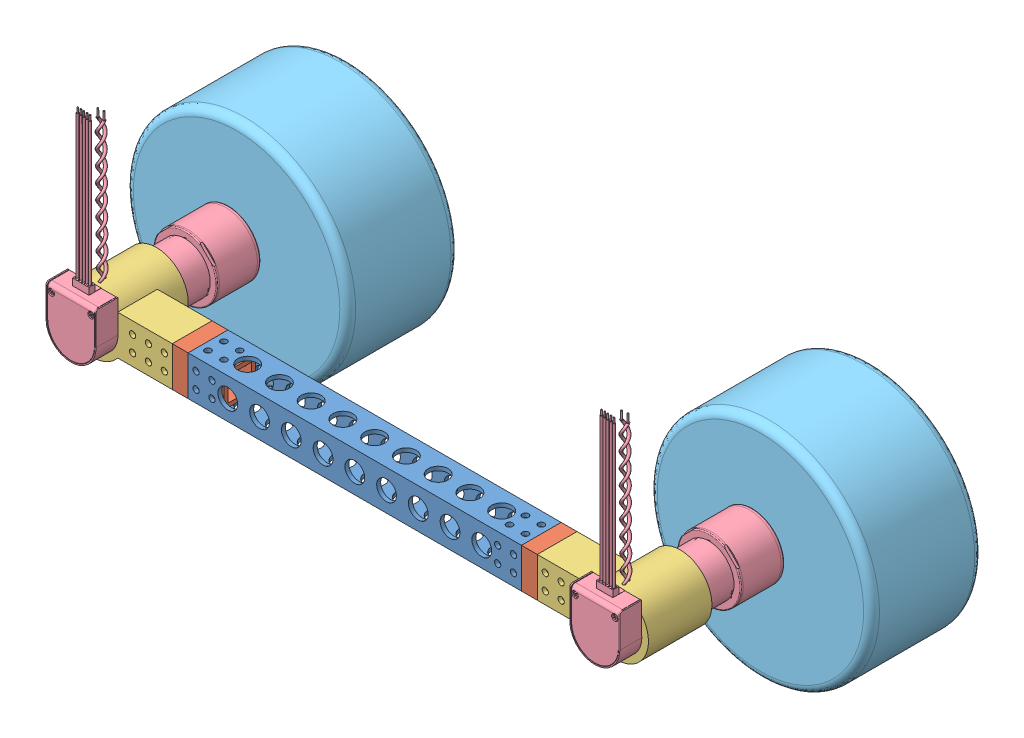
SolidWorks assembly One side drivetrain subassembly, configuration Default. Lengths in mm.
Overall size (596.9 246.35 221.71).
9 component instances, 5 part files, 20 mates.
Components (placement in the parent):
- 10.5in box extrusion-1: 10.5in box extrusion [Default] at (70.3566 -7.0157 32.9173) size (266.7 31.75 31.75)
- Extrusion to motor mount adapter-1: Extrusion to motor mount adapter [Default] at (108.4566 -10.1907 61.4923) x (0 0 1) z (-1 0 0) size (31.75 31.75 63.5)
- Extrusion to motor mount adapter-2: Extrusion to motor mount adapter [Default] at (-234.4434 -10.1907 36.0923) x (0 0 -1) z (1 0 0) size (31.75 31.75 63.5)
- Motor mount-1: Motor mount [Default] at (146.5566 -22.8907 13.8673) size (88.9 50.8 50.8)
- Motor mount-2: Motor mount [Default] at (-272.5434 -22.8907 13.8673) x (-1 0 0) z (0 0 1) size (88.9 50.8 50.8)
- GM9236S025-R1-SP_dc_motor_CAD-1: GM9236S025-R1-SP_dc_motor_CAD [Default] at (-272.5434 -22.8907 64.6673) size (52.61 175.4 145.51)
- GM9236S025-R1-SP_dc_motor_CAD-2: GM9236S025-R1-SP_dc_motor_CAD [Default] at (146.5566 -22.8907 64.6673) size (52.61 175.4 145.51)
- wheel-1: wheel [Default] at (146.5566 -31.2473 -139.2185) size (177.8 177.8 88.9)
- wheel-2: wheel [Default] at (-272.5434 -31.2473 -139.2185) size (177.8 177.8 88.9)
Mates (geometry in assembly coordinates):
- Coincident2: coincident anti-aligned: plane of 10.5in box extrusion-1 through (-196.3434 -10.1907 61.4923) normal (0 -1 0); plane of Extrusion to motor mount adapter-1 through (44.9566 -10.1907 36.0923) normal (0 1 0)
- Coincident3: coincident anti-aligned: plane of 10.5in box extrusion-1 through (-196.3434 -10.1907 61.4923) normal (0 0 -1); plane of Extrusion to motor mount adapter-1 through (44.9566 -10.1907 61.4923) normal (0 0 1)
- Coincident4: coincident anti-aligned: plane of 10.5in box extrusion-1 through (70.3566 -7.0157 64.6673) normal (1 0 0); plane of Extrusion to motor mount adapter-1 through (70.3566 -10.1907 61.4923) normal (-1 0 0)
- Coincident5: coincident anti-aligned: plane of 10.5in box extrusion-1 through (-196.3434 -10.1907 61.4923) normal (0 -1 0); plane of Extrusion to motor mount adapter-2 through (-170.9434 -10.1907 61.4923) normal (0 1 0)
- Coincident6: coincident anti-aligned: plane of 10.5in box extrusion-1 through (-196.3434 -10.1907 61.4923) normal (0 0 -1); plane of Extrusion to motor mount adapter-2 through (-170.9434 -10.1907 61.4923) normal (0 0 1)
- Coincident7: coincident anti-aligned: plane of 10.5in box extrusion-1 through (-196.3434 -7.0157 64.6673) normal (-1 0 0); plane of Extrusion to motor mount adapter-2 through (-196.3434 -10.1907 36.0923) normal (1 0 0)
- Coincident8: coincident anti-aligned: plane of Extrusion to motor mount adapter-1 through (83.0566 -10.1907 61.4923) normal (0 1 0); plane of Motor mount-1 through (121.1566 -10.1907 36.0923) normal (0 -1 0)
- Coincident9: coincident anti-aligned: plane of Extrusion to motor mount adapter-1 through (83.0566 -10.1907 61.4923) normal (0 0 1); plane of Motor mount-1 through (121.1566 -10.1907 61.4923) normal (0 0 -1)
- Coincident10: coincident anti-aligned: plane of Extrusion to motor mount adapter-1 through (83.0566 -10.1907 61.4923) normal (1 0 0); plane of Motor mount-1 through (83.0566 -7.0157 32.9173) normal (-1 0 0)
- Coincident11: coincident anti-aligned: plane of Extrusion to motor mount adapter-2 through (-209.0434 -35.5907 36.0923) normal (0 -1 0); plane of Motor mount-2 through (-247.1434 -35.5907 36.0923) normal (0 1 0)
- Coincident12: coincident anti-aligned: plane of Extrusion to motor mount adapter-2 through (-209.0434 -10.1907 36.0923) normal (0 0 -1); plane of Motor mount-2 through (-247.1434 -35.5907 36.0923) normal (0 0 1)
- Coincident13: coincident anti-aligned: plane of Extrusion to motor mount adapter-2 through (-209.0434 -10.1907 36.0923) normal (-1 0 0); plane of Motor mount-2 through (-209.0434 -38.7657 32.9173) normal (1 0 0)
- Concentric1: concentric anti-aligned: cylinder of Motor mount-2 through (-272.5434 -22.8907 64.6673) axis (0 0 -1) radius 20.066; cylinder of GM9236S025-R1-SP_dc_motor_CAD-1 through (-272.5434 -22.8907 -9.1451) axis (0 0 1) radius 20.066
- Coincident14: coincident anti-aligned: plane of Motor mount-2 through (-272.5434 -22.8907 64.6673) normal (0 0 1); plane of GM9236S025-R1-SP_dc_motor_CAD-1 through (-272.5434 -16.4491 64.6673) normal (0 0 -1)
- Concentric2: concentric anti-aligned: cylinder of Motor mount-1 through (146.5566 -22.8907 64.6673) axis (0 0 -1) radius 20.066; cylinder of GM9236S025-R1-SP_dc_motor_CAD-2 through (146.5566 -22.8907 -9.1451) axis (0 0 1) radius 20.066
- Coincident15: coincident anti-aligned: plane of Motor mount-1 through (146.5566 -22.8907 64.6673) normal (0 0 1); plane of GM9236S025-R1-SP_dc_motor_CAD-2 through (146.5566 -16.4491 64.6673) normal (0 0 -1)
- Concentric3: concentric anti-aligned: cylinder of GM9236S025-R1-SP_dc_motor_CAD-2 through (146.5566 -31.2473 -40.4379) axis (0 0 1) radius 3.1699; cylinder of wheel-1 through (146.5566 -31.2473 -50.3185) axis (0 0 -1) radius 6.35
- Distance1: distance = 6.35 mm anti-aligned: plane of GM9236S025-R1-SP_dc_motor_CAD-2 through (146.5566 -22.8907 -43.9685) normal (0 0 -1); plane of wheel-1 through (146.5566 -31.2473 -50.3185) normal (0 0 1)
- Concentric4: concentric anti-aligned: cylinder of GM9236S025-R1-SP_dc_motor_CAD-1 through (-272.5434 -31.2473 -40.4379) axis (0 0 1) radius 3.1699; cylinder of wheel-2 through (-272.5434 -31.2473 -50.3185) axis (0 0 -1) radius 6.35
- Distance2: distance = 6.35 mm anti-aligned: plane of wheel-2 through (-272.5434 -31.2473 -50.3185) normal (0 0 1); plane of GM9236S025-R1-SP_dc_motor_CAD-1 through (-272.5434 -22.8907 -43.9685) normal (0 0 -1)
